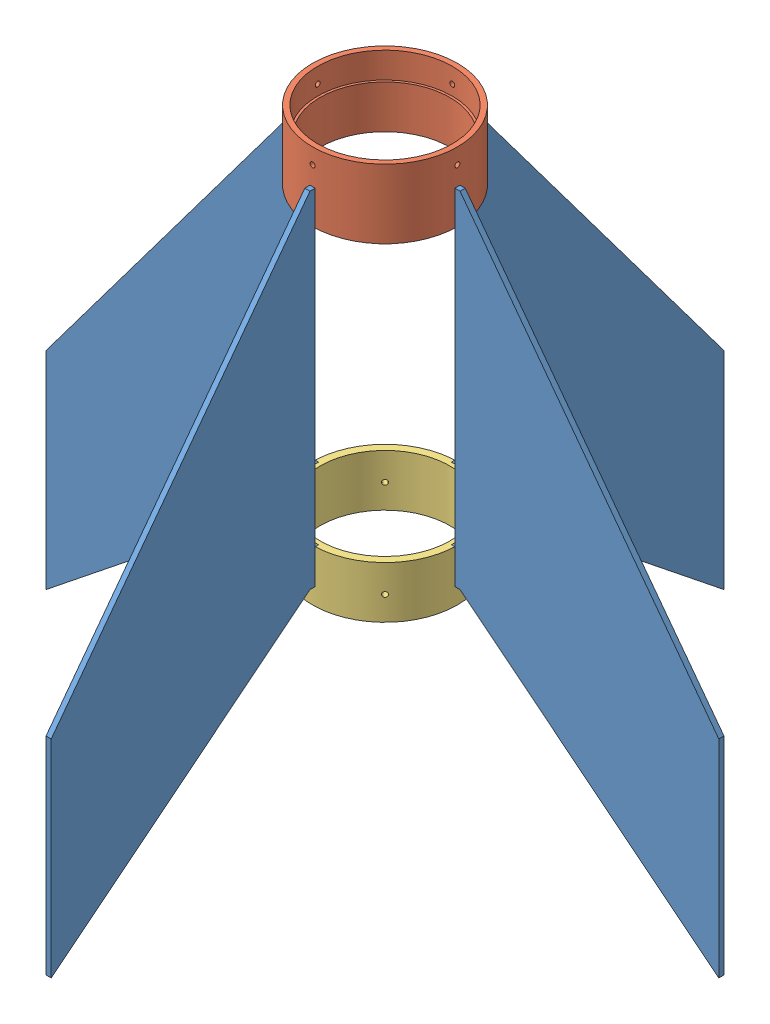
SolidWorks assembly SA aileronss, configuration Défaut. Lengths in mm.
Overall size (390 340 390).
6 component instances, 3 part files, 7 mates.
Components (placement in the parent):
- Aileron-1: Aileron [Défaut] at (68.301 206.6294 318.5) size (155 320 3)
- Bague Ailerons-2: Bague Ailerons [Défaut] at (108.301 186.6294 320) x (0 1 0) z (0 0 1) size (40 84 84)
- Aileron-2: Aileron [Défaut] at (109.801 206.6294 280) x (0 0 1) z (-1 0 0) size (155 320 3)
- Aileron-3: Aileron [Défaut] at (148.301 206.6294 321.5) x (-1 0 0) z (0 0 -1) size (155 320 3)
- Aileron-4: Aileron [Défaut] at (106.801 206.6294 360) x (0 0 -1) z (1 0 0) size (155 320 3)
- Bague Ailerons 2-1: Bague Ailerons 2 [Défaut] at (108.301 -3.3706 320) x (0 1 0) z (1 0 0) size (30 84 84)
Mates (geometry in assembly coordinates):
- Coïncidente1: coincident anti-aligned: plane of Aileron-1 through (68.301 206.6294 321.5) normal (1 0 0); plane of Bague Ailerons-2 through (68.301 206.6294 318.5) normal (-1 0 0)
- Coïncidente2: coincident anti-aligned: plane of Aileron-1 through (68.301 206.6294 318.5) normal (0 0 -1); plane of Bague Ailerons-2 through (53.301 206.6294 318.5) normal (0 0 1)
- Coïncidente3: coincident anti-aligned: plane of Aileron-1 through (68.301 206.6294 321.5) normal (0 1 0); plane of Bague Ailerons-2 through (108.301 206.6294 320) normal (0 -1 0)
- Coaxiale1: concentric aligned: cylinder of Bague Ailerons-2 through (108.301 186.6294 320) axis (0 -1 0) radius 42; cylinder of Bague Ailerons 2-1 through (108.301 -3.3706 320) axis (0 -1 0) radius 42
- Coïncidente4: coincident anti-aligned: plane of Aileron-1 through (68.301 206.6294 318.5) normal (0 0 -1); plane of Bague Ailerons 2-1 through (68.301 6.6294 318.5) normal (0 0 1)
- Coïncidente5: coincident aligned: line of Aileron-1 through (68.301 6.6294 321.5) axis (0 0 -1); line of Bague Ailerons 2-1 through (68.301 6.6294 321.5) axis (0 0 -1)
- Coïncidente7: coincident aligned: plane of Bague Ailerons-2 through (108.301 186.6294 320) normal (0 0 1); plane of Bague Ailerons 2-1
